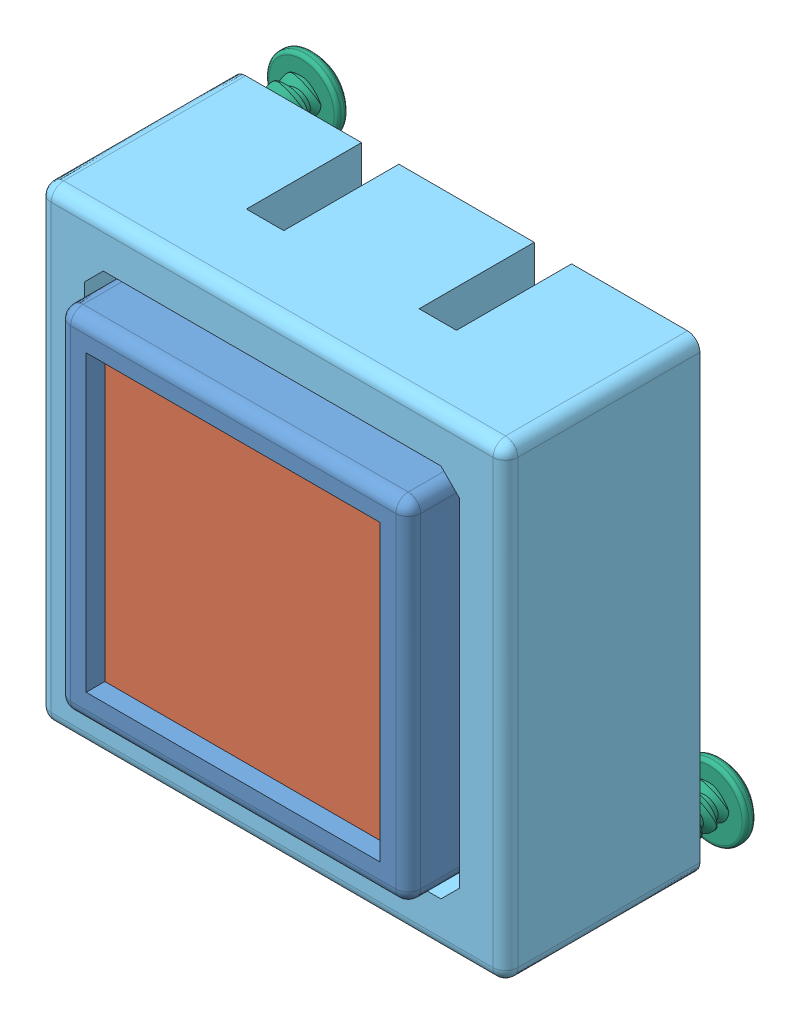
SolidWorks assembly .55 SQ Indicator, configuration BLANK. Lengths in mm.
Overall size (20.5 20.5 12.08).
10 component instances, 7 part files, 10 mates.
Components (placement in the parent):
- .55 SQ Indicator Bezel-1: .55 SQ Indicator Bezel [Default] at origin size (14.29 14.29 2.54)
- .55 SQ Indicator Legend Cover-1: .55 SQ Indicator Legend Cover [BLANK] at (0 0 -0.762) x (-1 0 0) z (0 0 -1) size (12.57 12.57 0.76)
- .55 SQ Indicator Legend-1: .55 SQ Indicator Legend [BLANK] at (0 0 -1.524) x (-1 0 0) z (0 0 -1) size (12.57 12.57 0.13)
- .55 SQ Indicator Actuator-1: .55 SQ Indicator Actuator [Default] at (0 0 -1.651) x (-1 0 0) z (0 0 -1) size (14.1 16.64 6.35)
- .55 SQ Indicator Legend Diffuser-1: .55 SQ Indicator Legend Diffuser [Green] at (-23.4937 80.9593 -1.651) x (1 0 0) z (0 0 -1) size (11.3 5.28 0.13) (suppressed, hidden)
- .55 SQ Indicator Legend Diffuser-2: .55 SQ Indicator Legend Diffuser [Amber] at (-23.4937 74.9268 -1.651) x (1 0 0) z (0 0 -1) size (11.3 5.28 0.13) (suppressed, hidden)
- .55 SQ Indicator Base-1: .55 SQ Indicator Base [Default] at (0 0 -1.5875) size (19.05 19.05 7.94)
- 99461A505 - PHS, 0-42 X .125, SELF TAPPING, 18-8-1: 99461A505 - PHS, 0-42 X .125, SELF TAPPING, 18-8 [99461A505] at (12.7 -106.3625 -6.4135) x (1 0 0) z (0 0 -1) size (2.95 2.95 4.36)
- 99461A505 - PHS, 0-42 X .125, SELF TAPPING, 18-8-2: 99461A505 - PHS, 0-42 X .125, SELF TAPPING, 18-8 [99461A505] at (21.0235 -114.686 -9.525) x (-0.923728 -0.383049 0) z (0 0 -1) size (2.95 2.95 4.36)
- 99461A505 - PHS, 0-42 X .125, SELF TAPPING, 18-8-3: 99461A505 - PHS, 0-42 X .125, SELF TAPPING, 18-8 [99461A505] at (4.3765 -98.039 -9.525) x (-0.923728 -0.383049 0) z (0 0 -1) size (2.95 2.95 4.36)
Mates (geometry in assembly coordinates):
- Coincident72: coincident anti-aligned: plane of .55 SQ Indicator Legend-1 through (0 0 -1.651) normal (0 0 -1); plane of .55 SQ Indicator Legend Diffuser-1 through (-23.4937 80.9593 -1.651) normal (0 0 1)
- Width7: width anti-aligned: plane of .55 SQ Indicator Legend Diffuser-1 through (18.3515 -105.9878 -1.778) normal (0 -1 0); plane of .55 SQ Indicator Legend Diffuser-1 through (7.0485 -100.7047 -1.778) normal (0 1 0); plane of .55 SQ Indicator Actuator-1 through (6.4135 -106.1085 -8.001) normal (0 1 0); plane of .55 SQ Indicator Actuator-1 through (6.4135 -100.584 -8.001) normal (0 -1 0)
- Width8: width anti-aligned: plane of .55 SQ Indicator Legend Diffuser-1 through (7.0485 -105.9878 -1.778) normal (-1 0 0); plane of .55 SQ Indicator Legend Diffuser-1 through (18.3515 -100.7047 -1.778) normal (1 0 0); plane of .55 SQ Indicator Actuator-1 through (6.9215 -112.649 -8.001) normal (1 0 0); plane of .55 SQ Indicator Actuator-1 through (18.4785 -100.076 -8.001) normal (-1 0 0)
- Width9: width anti-aligned: plane of .55 SQ Indicator Actuator-1 through (6.4135 -106.6165 -8.001) normal (0 -1 0); plane of .55 SQ Indicator Legend Diffuser-2 through (18.9865 -112.141 -8.001) normal (0 1 0); plane of .55 SQ Indicator Actuator-1 through (7.0485 -106.7371 -1.778) normal (0 1 0); plane of .55 SQ Indicator Legend Diffuser-2 through (18.3515 -112.0204 -1.778) normal (0 -1 0)
- Concentric7: concentric anti-aligned: cylinder of .55 SQ Indicator Actuator-1 through (12.7 -106.3625 -8.001) axis (0 0 -1) radius 0.5956; cylinder of 99461A505 - PHS, 0-42 X .125, SELF TAPPING, 18-8-1 through (12.7 -106.3625 -8.9916) axis (0 0 1) radius 1.4732
- Coincident76: coincident anti-aligned: plane of .55 SQ Indicator Actuator-1 through (0 0 -8.001) normal (0 0 -1); plane of 99461A505 - PHS, 0-42 X .125, SELF TAPPING, 18-8-1 through (12.7 -106.3625 -8.001) normal (0 0 1)
- Coincident70: coincident aligned: plane of .55 SQ Indicator Legend Diffuser-1 through (-23.4937 80.9593 -1.778) normal (0 0 -1); plane of .55 SQ Indicator Legend Diffuser-2 through (-23.4937 74.9268 -1.778) normal (0 0 -1)
- Coincident71: coincident aligned: plane of .55 SQ Indicator Legend Diffuser-1 through (7.0485 -105.9878 -1.778) normal (-1 0 0); plane of .55 SQ Indicator Legend Diffuser-2 through (7.0485 -112.0204 -1.778) normal (-1 0 0)
- Concentric8: concentric anti-aligned: cylinder of .55 SQ Indicator Base-1 through (21.0235 -114.686 -9.525) axis (0 0 -1) radius 0.5956; cylinder of 99461A505 - PHS, 0-42 X .125, SELF TAPPING, 18-8-2 through (21.0235 -114.686 -12.1031) axis (0 0 1) radius 1.4732
- Concentric9: concentric anti-aligned: cylinder of .55 SQ Indicator Base-1 through (4.3765 -98.039 -9.525) axis (0 0 -1) radius 0.5956; cylinder of 99461A505 - PHS, 0-42 X .125, SELF TAPPING, 18-8-3 through (4.3765 -98.039 -12.1031) axis (0 0 1) radius 1.4732
